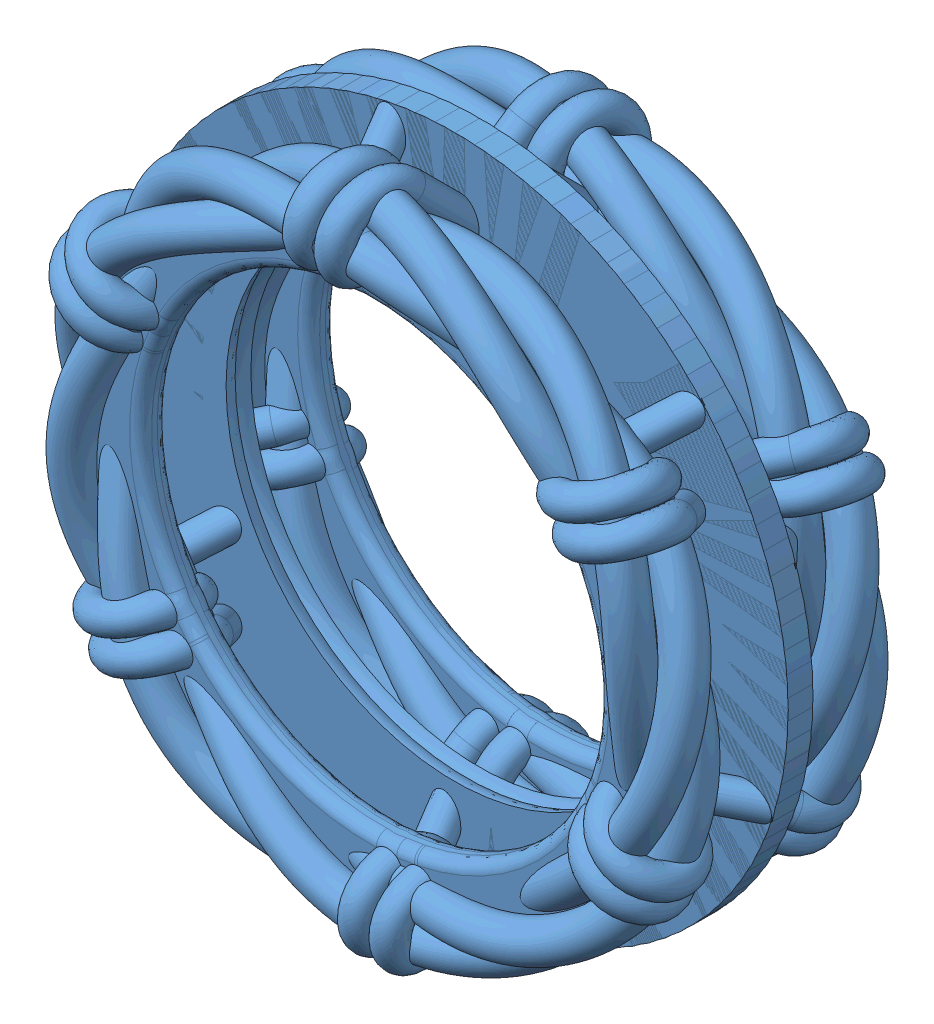
SolidWorks assembly Assem2, configuration Default. Lengths in mm.
Overall size (31.24 31.24 12.49).
2 component instances, 1 part files, 2 mates.
Components (placement in the parent):
- New Ring-1: New Ring [Default] at origin size (31.24 31.24 6.81)
- New Ring-2: New Ring [Default] at (0 0 7.747) x (-1 0 0) z (0 0 -1) size (31.24 31.24 6.81)
Mates (geometry in assembly coordinates):
- Coincident1: coincident: plane of New Ring-1 through (0 0 3.302) normal (0 0 -1); plane of New Ring-2 through (0 0 3.302) normal (0 0 -1)
- Concentric1: concentric anti-aligned: circle of New Ring-1; circle of New Ring-2
